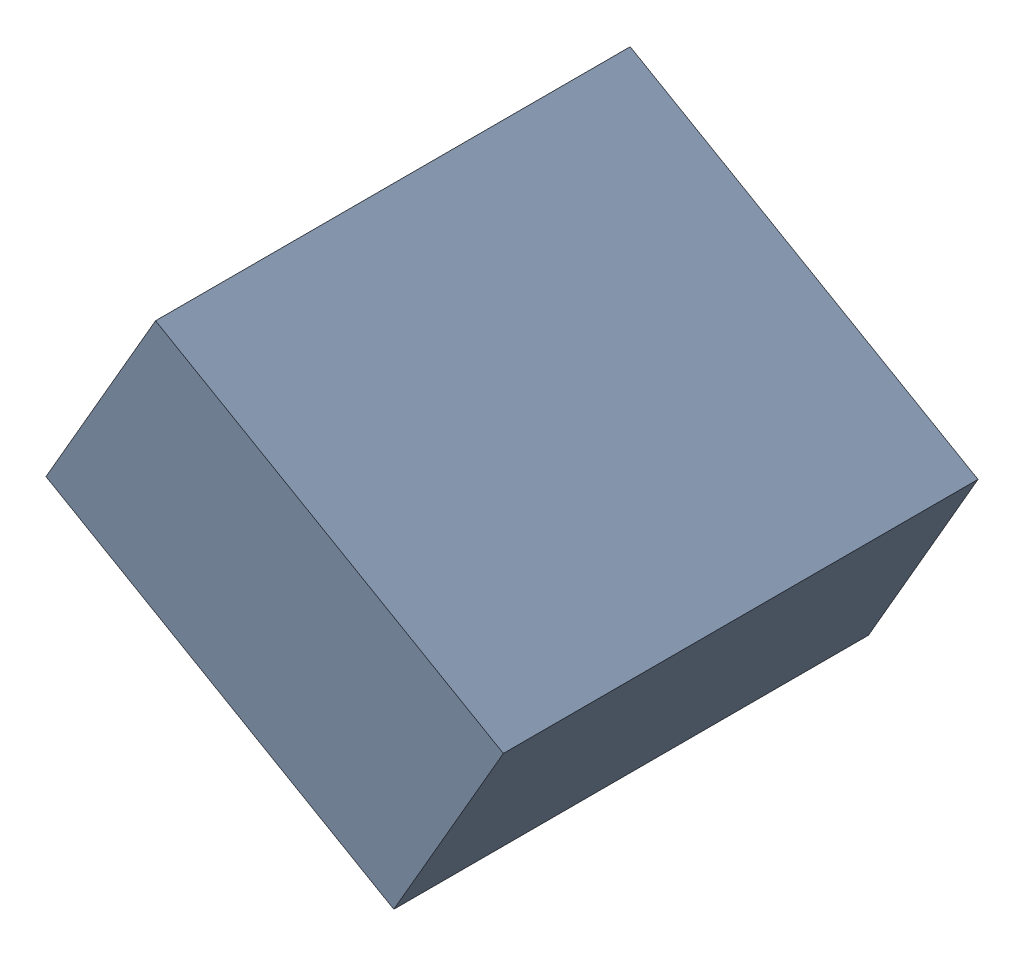
SolidWorks assembly C23_TDA3, configuration Standard. Lengths in mm.
Overall size (1.25 1.07 1.3).
2 component instances, 1 part files, 0 mates.
Components (placement in the parent):
- 885543056-1: 885543056 [Standard] at (40.7966 -31.4296 0) size (1.25 1.07 1.3)
  - Extruded_23-1: Extruded_23 [Standard] at origin size (1.25 1.07 1.3)
